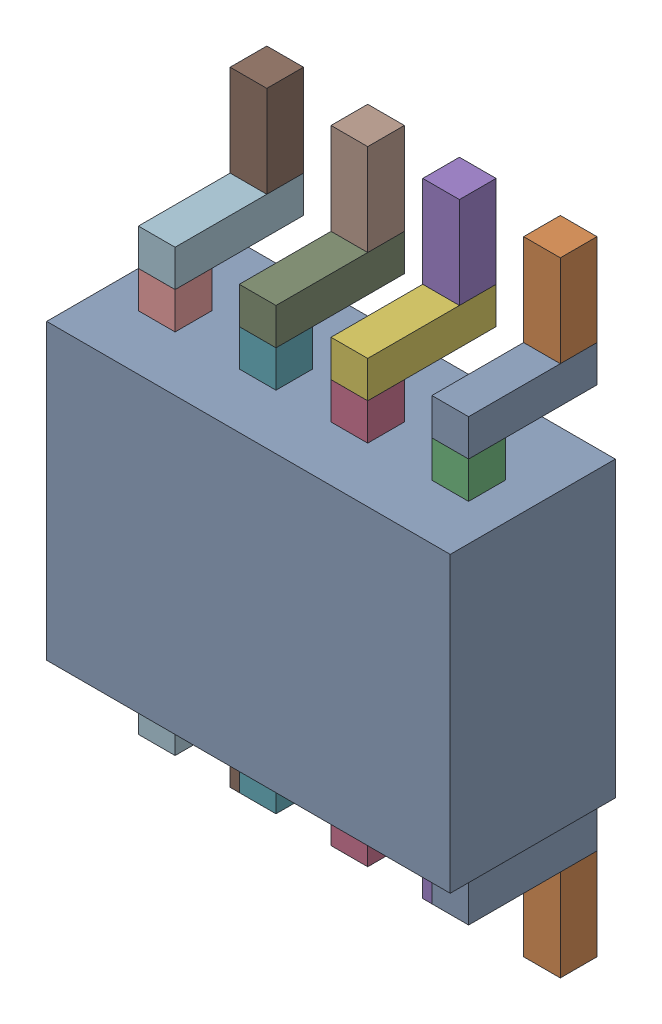
SolidWorks assembly U24, configuration Default. Lengths in mm.
Overall size (2.2 3.4 1).
50 component instances, 4 part files, 0 mates.
Components (placement in the parent):
- 836755056-1: 836755056 [Default] at (131.5001 67.5001 0) size (0.2 0.2 0.7)
  - Extruded_28-1: Extruded_28 [Default] at origin size (0.2 0.2 0.7)
- 836755824-1: 836755824 [Default] at (131.5001 67.8501 0) size (0.2 0.5 0.2)
  - Extruded_29-1: Extruded_29 [Default] at origin size (0.2 0.5 0.2)
- 836755440-1: 836755440 [Default] at (131.5001 67.3001 0.5) size (0.2 0.2 0.2)
  - Extruded_30-1: Extruded_30 [Default] at origin size (0.2 0.2 0.2)
- 836755440-2: 836755440 [Default] at (130.9501 67.3001 0.5) size (0.2 0.2 0.2)
  - Extruded_30-1: Extruded_30 [Default] at origin size (0.2 0.2 0.2)
- 836755824-2: 836755824 [Default] at (130.9501 67.8501 0) size (0.2 0.5 0.2)
  - Extruded_29-1: Extruded_29 [Default] at origin size (0.2 0.5 0.2)
- 836755056-2: 836755056 [Default] at (130.9501 67.5001 0) size (0.2 0.2 0.7)
  - Extruded_28-1: Extruded_28 [Default] at origin size (0.2 0.2 0.7)
- 836755440-3: 836755440 [Default] at (130.4501 67.3001 0.5) size (0.2 0.2 0.2)
  - Extruded_30-1: Extruded_30 [Default] at origin size (0.2 0.2 0.2)
- 836755824-3: 836755824 [Default] at (130.4501 67.8501 0) size (0.2 0.5 0.2)
  - Extruded_29-1: Extruded_29 [Default] at origin size (0.2 0.5 0.2)
- 836755056-3: 836755056 [Default] at (130.4501 67.5001 0) size (0.2 0.2 0.7)
  - Extruded_28-1: Extruded_28 [Default] at origin size (0.2 0.2 0.7)
- 836755440-4: 836755440 [Default] at (129.9001 67.3001 0.5) size (0.2 0.2 0.2)
  - Extruded_30-1: Extruded_30 [Default] at origin size (0.2 0.2 0.2)
- 836755824-4: 836755824 [Default] at (129.9001 67.8501 0) size (0.2 0.5 0.2)
  - Extruded_29-1: Extruded_29 [Default] at origin size (0.2 0.5 0.2)
- 836755056-4: 836755056 [Default] at (129.9001 67.5001 0) size (0.2 0.2 0.7)
  - Extruded_28-1: Extruded_28 [Default] at origin size (0.2 0.2 0.7)
- 836755056-5: 836755056 [Default] at (131.5001 65.3001 0) size (0.2 0.2 0.7)
  - Extruded_28-1: Extruded_28 [Default] at origin size (0.2 0.2 0.7)
- 836755824-5: 836755824 [Default] at (131.5001 64.9501 0) size (0.2 0.5 0.2)
  - Extruded_29-1: Extruded_29 [Default] at origin size (0.2 0.5 0.2)
- 836755440-5: 836755440 [Default] at (131.5001 65.5001 0.5) size (0.2 0.2 0.2)
  - Extruded_30-1: Extruded_30 [Default] at origin size (0.2 0.2 0.2)
- 836755056-6: 836755056 [Default] at (130.9501 65.3001 0) size (0.2 0.2 0.7)
  - Extruded_28-1: Extruded_28 [Default] at origin size (0.2 0.2 0.7)
- 836755824-6: 836755824 [Default] at (130.9501 64.9501 0) size (0.2 0.5 0.2)
  - Extruded_29-1: Extruded_29 [Default] at origin size (0.2 0.5 0.2)
- 836755440-6: 836755440 [Default] at (130.9501 65.5001 0.5) size (0.2 0.2 0.2)
  - Extruded_30-1: Extruded_30 [Default] at origin size (0.2 0.2 0.2)
- 836755056-7: 836755056 [Default] at (130.4501 65.3001 0) size (0.2 0.2 0.7)
  - Extruded_28-1: Extruded_28 [Default] at origin size (0.2 0.2 0.7)
- 836755824-7: 836755824 [Default] at (130.4501 64.9501 0) size (0.2 0.5 0.2)
  - Extruded_29-1: Extruded_29 [Default] at origin size (0.2 0.5 0.2)
- 836755440-7: 836755440 [Default] at (130.4501 65.5001 0.5) size (0.2 0.2 0.2)
  - Extruded_30-1: Extruded_30 [Default] at origin size (0.2 0.2 0.2)
- 836755440-8: 836755440 [Default] at (129.9001 65.5001 0.5) size (0.2 0.2 0.2)
  - Extruded_30-1: Extruded_30 [Default] at origin size (0.2 0.2 0.2)
- 836755824-8: 836755824 [Default] at (129.9001 64.9501 0) size (0.2 0.5 0.2)
  - Extruded_29-1: Extruded_29 [Default] at origin size (0.2 0.5 0.2)
- 836755056-8: 836755056 [Default] at (129.9001 65.3001 0) size (0.2 0.2 0.7)
  - Extruded_28-1: Extruded_28 [Default] at origin size (0.2 0.2 0.7)
- 836755952-1: 836755952 [Default] at (130.7 66.4 0.1) size (2.2 1.6 0.9)
  - Extruded_31-1: Extruded_31 [Default] at origin size (2.2 1.6 0.9)
